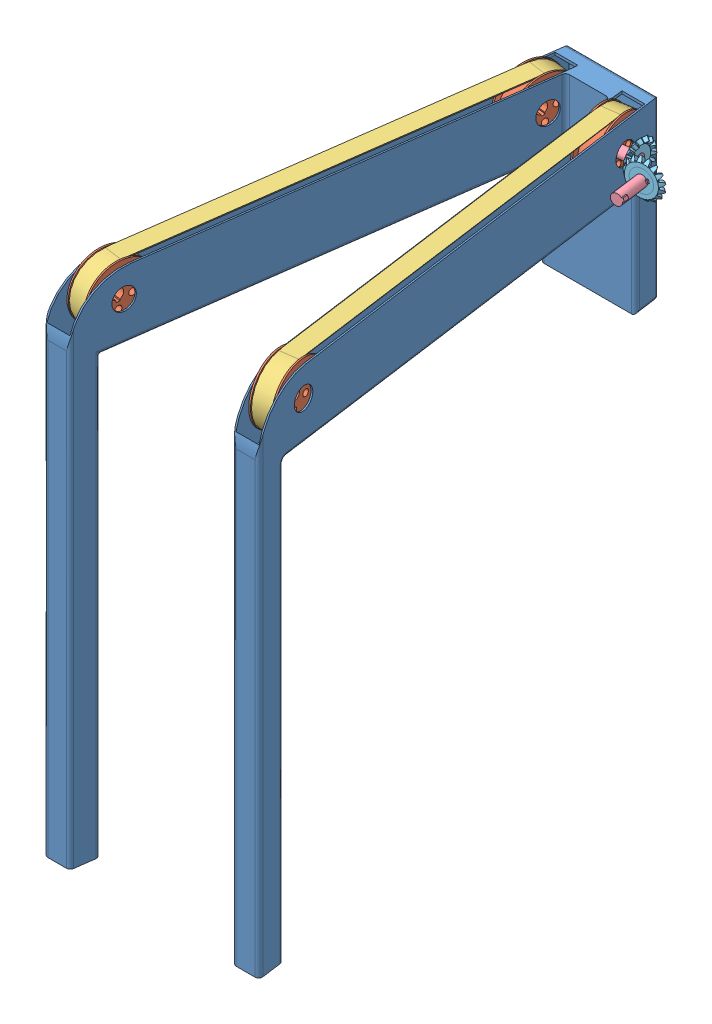
SolidWorks assembly TASK ASSEMBLY0.2, configuration Default. Lengths in mm.
Overall size (394.85 956.67 850.84).
12 component instances, 5 part files, 34 mates.
Components (placement in the parent):
- Frame-1: Frame [Default] at (0.1812 333.9908 -374.6199) size (394.85 924 850.5)
- pully-1: pully [Default] at (67.9292 405.9908 -348.9134) x (-0.134543 0.13588 -0.981547) z (-0.990736 0 0.135802) size (120 120 40)
- pully-2: pully [Default] at (161.9045 405.9908 336.6758) x (0.102111 0.659266 0.744944) z (-0.990736 0 0.135802) size (120 120 40)
- pully-3: pully [Default] at (-161.5422 405.9908 336.6758) x (0.135638 0.049218 -0.989535) z (-0.990736 0 -0.135802) size (120 120 40)
- pully-4: pully [Default] at (-67.5669 405.9908 -348.9134) x (0.132293 0.225881 -0.96513) z (-0.990736 0 -0.135802) size (120 120 40)
- belt-1: belt [Default] at (161.9054 405.9908 336.6757) x (-0.135802 0 -0.990736) z (-0.990736 0 0.135802) size (810 118 34)
- belt-2: belt [Default] at (-161.5413 405.9908 336.676) x (0.135802 0 -0.990736) z (-0.990736 0 -0.135802) size (810 118 34)
- 20 D shaft-1: 20 D shaft [Default] at (85.7625 405.9908 -351.3579) x (-0.134543 0.13588 -0.981547) z (-0.990736 0 0.135802) size (20 22.75 60)
- 20 D shaft-2: 20 D shaft [Default] at (-87.3816 405.9908 -351.6295) x (-0.132293 -0.225881 0.96513) z (0.990736 0 0.135802) size (20 22.75 60) (hidden)
- straight bevel pinion_am-1: straight bevel pinion_am [Metric - Straight bevel pinion 4M16PT 16GT 20PA 8FW ---16O40H30MD20S1] at (109.1443 405.9908 -354.5629) x (0.990736 0 -0.135802) z (-0.134543 0.13588 -0.981547) size (12.58 69.22 69.22)
- straight bevel pinion_am-3: straight bevel pinion_am [Metric - Straight bevel pinion 4M16PT 16GT 20PA 8FW ---16O40H30MD20S1] at (149.9262 406.1586 -323.6137) x (-0.135801 -0.004634 -0.990725) z (0.346169 -0.937183 -0.043067) size (12.58 69.22 69.22)
- 20 D shaft-3: 20 D shaft [Default] at (153.1312 406.2679 -300.2321) x (0.346169 -0.937183 -0.043067) z (0.135801 0.004634 0.990725) size (20 22.75 60)
Mates (geometry in assembly coordinates):
- Concentric1: concentric aligned: cylinder of Frame-1 through (10.4666 405.9908 -341.0369) axis (0.990736 0 -0.135802) radius 20; cylinder of pully-1 through (48.1145 405.9908 -346.1974) axis (0.990736 0 -0.135802) radius 10
- Width1: width anti-aligned: plane of pully-1 through (87.744 405.9908 -351.6295) normal (0.990736 0 -0.135802); plane of Frame-1 through (48.1145 405.9908 -346.1974) normal (-0.990736 0 0.135802); plane of pully-1 through (79.0783 457.9908 -422.2125) normal (-0.990736 0 0.135802); plane of Frame-1 through (43.1534 457.9908 -375.0273) normal (0.990736 0 -0.135802)
- Concentric2: concentric aligned: cylinder of Frame-1 through (104.4419 405.9908 344.5524) axis (0.990736 0 -0.135802) radius 20; cylinder of pully-2 through (142.0898 405.9908 339.3919) axis (0.990736 0 -0.135802) radius 10
- Width2: width anti-aligned: plane of pully-2 through (181.7193 405.9908 333.9598) normal (0.990736 0 -0.135802); plane of Frame-1 through (142.0898 405.9908 339.3919) normal (-0.990736 0 0.135802); plane of pully-2 through (79.0783 457.9908 -422.2125) normal (-0.990736 0 0.135802); plane of Frame-1 through (43.1534 457.9908 -375.0273) normal (0.990736 0 -0.135802)
- Concentric3: concentric aligned: cylinder of Frame-1 through (-10.1042 405.9908 -341.0369) axis (-0.990736 0 -0.135802) radius 20; cylinder of pully-4 through (-67.5669 405.9908 -348.9134) axis (-0.990736 0 -0.135802) radius 54
- Concentric4: concentric aligned: cylinder of Frame-1 through (-104.0795 405.9908 344.5524) axis (-0.990736 0 -0.135802) radius 20; cylinder of pully-3 through (-161.5422 405.9908 336.6758) axis (-0.990736 0 -0.135802) radius 54
- Width3: width aligned: plane of pully-4 through (-47.7522 405.9908 -346.1974) normal (0.990736 0 0.135802); plane of Frame-1 through (-87.3816 405.9908 -351.6295) normal (-0.990736 0 -0.135802); plane of pully-4 through (-194.4019 457.9908 421.7651) normal (0.990736 0 0.135802); plane of Frame-1 through (-42.791 457.9908 -375.0273) normal (-0.990736 0 -0.135802)
- Width4: width aligned: plane of pully-3 through (-181.3569 405.9908 333.9598) normal (-0.990736 0 -0.135802); plane of Frame-1 through (-141.7275 405.9908 339.3919) normal (0.990736 0 0.135802); plane of pully-3 through (-42.791 457.9908 -375.0273) normal (-0.990736 0 -0.135802); plane of Frame-1 through (-194.4019 457.9908 421.7651) normal (0.990736 0 0.135802)
- Concentric5: concentric anti-aligned: cylinder of pully-1 through (67.9292 405.9908 -348.9134) axis (-0.990736 0 0.135802) radius 54; cylinder of belt-1 through (67.9301 405.9908 -348.9135) axis (0.990736 0 -0.135802) radius 54
- Coincident1: coincident anti-aligned: circle of pully-2; cylinder of belt-1 through (161.9054 405.9908 336.6757) axis (0.990736 0 -0.135802) radius 54
- Coincident4: coincident: point of pully-2; point of belt-1
- Concentric7: concentric anti-aligned: cylinder of pully-4 through (-67.5669 405.9908 -348.9134) axis (-0.990736 0 -0.135802) radius 54; cylinder of belt-2 through (-67.566 405.9908 -348.9133) axis (0.990736 0 0.135802) radius 54
- Concentric8: concentric anti-aligned: cylinder of pully-3 through (-161.5422 405.9908 336.6758) axis (-0.990736 0 -0.135802) radius 54; cylinder of belt-2 through (-161.5413 405.9908 336.676) axis (0.990736 0 0.135802) radius 54
- Coincident5: coincident: circle of pully-3; point of belt-2
- Concentric9: concentric aligned: cylinder of pully-1 through (48.1145 405.9908 -346.1974) axis (0.990736 0 -0.135802) radius 10; cylinder of 20 D shaft-1 through (56.0404 405.9908 -347.2838) axis (0.990736 0 -0.135802) radius 10
- Coincident6: coincident aligned: plane of pully-1 through (56.0404 405.9908 -347.2838) normal (-0.990736 0 0.135802); plane of 20 D shaft-1 through (56.0404 405.9908 -347.2838) normal (-0.990736 0 0.135802)
- Coincident7: coincident anti-aligned: plane of pully-1 through (47.5353 396.9699 -350.4232) normal (0.134543 -0.13588 0.981547); plane of 20 D shaft-1 through (64.3182 393.7717 -353.1664) normal (-0.134543 0.13588 -0.981547)
- Concentric10: concentric anti-aligned: cylinder of pully-4 through (-87.3816 405.9908 -351.6295) axis (0.990736 0 0.135802) radius 10; cylinder of 20 D shaft-2 through (-57.6595 405.9908 -347.5554) axis (-0.990736 0 -0.135802) radius 10
- Coincident8: coincident anti-aligned: plane of pully-4 through (-87.4865 396.0423 -350.8639) normal (0.132293 0.225881 -0.96513); plane of 20 D shaft-2 through (-66.5821 392.8976 -348.7344) normal (-0.132293 -0.225881 0.96513)
- Coincident9: coincident aligned: plane of pully-4 through (-57.6595 405.9908 -347.5554) normal (0.990736 0 0.135802); plane of 20 D shaft-2 through (-57.6595 405.9908 -347.5554) normal (0.990736 0 0.135802)
- Coincident11: coincident aligned: plane of 20 D shaft-1 through (115.4846 405.9908 -355.4319) normal (0.990736 0 -0.135802); plane of straight bevel pinion_am-1 through (115.4846 405.9908 -355.4319) normal (0.990736 0 -0.135802)
- Concentric12: concentric anti-aligned: cylinder of 20 D shaft-1 through (56.0404 405.9908 -347.2838) axis (0.990736 0 -0.135802) radius 10; cylinder of straight bevel pinion_am-1 through (145.0101 405.9908 -359.4791) axis (-0.990736 0 0.135802) radius 10
- Coincident12: coincident anti-aligned: plane of 20 D shaft-1; plane of straight bevel pinion_am-1
- Perpendicular1: perpendicular: line of straight bevel pinion_am-1 through (116.1087 405.9908 -355.5175) axis (0.990736 0 -0.135802); line of straight bevel pinion_am-3 through (149.0572 406.1289 -329.9539) axis (0.135801 0.004634 0.990725)
- Coincident14: coincident: point of straight bevel pinion_am-1; point of straight bevel pinion_am-3
- Perpendicular2: perpendicular: line of straight bevel pinion_am-1 through (99.237 405.9908 -353.2048) axis (0.990736 0 -0.135802); line of straight bevel pinion_am-3 through (151.2842 406.2049 -313.7065) axis (-0.135801 -0.004634 -0.990725)
- GearMate1: gear = 20 : 20 mm: cylinder of straight bevel pinion_am-1 through (145.0101 405.9908 -359.4791) axis (-0.990736 0 0.135802) radius 10; cylinder of straight bevel pinion_am-3 through (145.0101 405.9908 -359.4791) axis (0.135801 0.004634 0.990725) radius 10
- Parallel2: parallel aligned: plane of straight bevel pinion_am-3 through (149.9262 406.1586 -323.6137) normal (0.135801 0.004634 0.990725)
- Concentric13: concentric anti-aligned: cylinder of straight bevel pinion_am-3 through (145.0101 405.9908 -359.4791) axis (0.135801 0.004634 0.990725) radius 10; cylinder of 20 D shaft-3 through (157.2052 406.407 -270.5104) axis (-0.135801 -0.004634 -0.990725) radius 10
- Coincident18: coincident aligned: plane of straight bevel pinion_am-3 through (149.0572 406.1289 -329.9539) normal (-0.135801 -0.004634 -0.990725); plane of 20 D shaft-3 through (149.0572 406.1289 -329.9539) normal (-0.135801 -0.004634 -0.990725)
- Coincident19: coincident anti-aligned: plane of straight bevel pinion_am-3 through (155.8537 413.2671 -360.9995) normal (0.346169 -0.937183 -0.043067); plane of 20 D shaft-3 through (161.0719 413.4277 -322.5507) normal (-0.346169 0.937183 0.043067)
- GearMate2: gear = 20 : 20 mm: cylinder of pully-2 through (142.0898 405.9908 339.3919) axis (0.990736 0 -0.135802) radius 10; cylinder of pully-1 through (48.1145 405.9908 -346.1974) axis (0.990736 0 -0.135802) radius 10
- GearMate3: gear = 20 : 20 mm: cylinder of pully-3 through (-181.3569 405.9908 333.9598) axis (0.990736 0 0.135802) radius 10; cylinder of pully-2 through (142.0898 405.9908 339.3919) axis (0.990736 0 -0.135802) radius 10
- GearMate4: gear = 20 : 20 mm: cylinder of pully-4 through (-87.3816 405.9908 -351.6295) axis (0.990736 0 0.135802) radius 10; cylinder of pully-2 through (142.0898 405.9908 339.3919) axis (0.990736 0 -0.135802) radius 10
